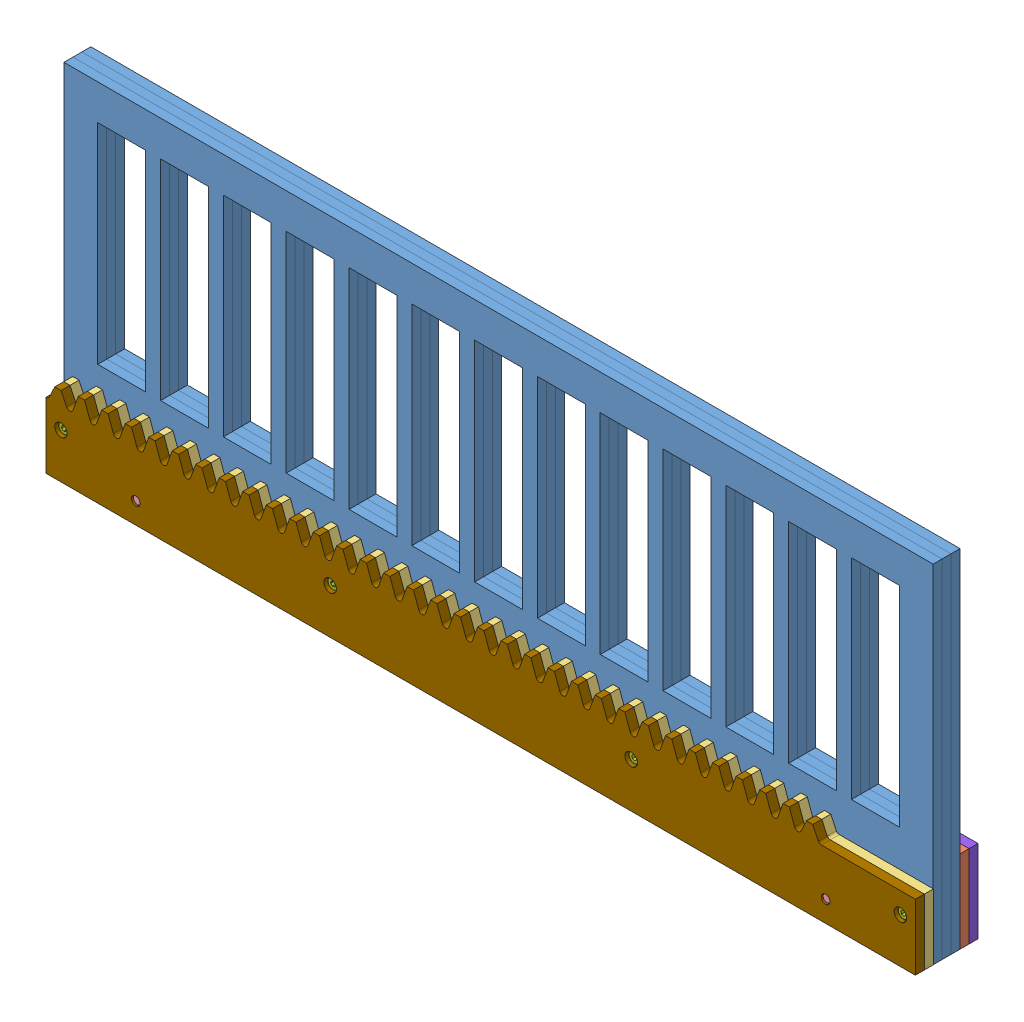
SolidWorks assembly grille-complet, configuration Défaut. Lengths in mm.
Overall size (290.66 121.96 23).
19 component instances, 9 part files, 44 mates.
Components (placement in the parent):
- grille-1: grille [Défaut] at (-123.12 -59.7841 0) size (290.6 116 3)
- grille-bas-1-1: grille-bas-1 [Défaut] at (-123.1215 -59.7841 -3) size (290.6 27.62 3)
- grille-cremaillere-1-1: grille-cremaillere-1 [Défaut] at (151.8274 -59.7841 12) x (-1 0 0) z (0 0 -1) size (290.66 27.62 3)
- grille-axe-d3x20-1: grille-axe-d3x20 [Défaut] at (-97.0485 -52.7841 -5.5) x (0.990021 0.140917 0) z (0.140917 -0.990021 0) size (3 20 3)
- grille-poulie-d20-1: grille-poulie-d20 [Défaut] at (-97.0485 -52.7841 3.2376) x (0.249924 -0.968265 0) z (-0.968265 -0.249924 0) size (20.21 12 20.21)
- grille-poulie-d20-2: grille-poulie-d20 [Défaut] at (133.5488 -52.7841 3.6069) x (0.939295 0.34311 0) z (0.34311 -0.939295 0) size (20.21 12 20.21)
- grille-axe-d3x20-2: grille-axe-d3x20 [Défaut] at (133.5488 -52.7841 -5.5) x (0.725366 0.688363 0) z (0.688363 -0.725366 0) size (3 20 3)
- ecrou-h-1: ecrou-h [6007 HU M2] at (-122.0485 -44.7841 -3) x (1 0 0) z (0 -1 0) size (4 1.6 4.62)
- vis-chc-1: vis-chc [Vis CHC M2x20] at (-122.0485 -44.7841 12) x (-0.903483 -0.428623 0) z (-0.428623 0.903483 0) size (3.8 22 3.8)
- vis-chc-2: vis-chc [Vis CHC M2x20] at (-32.0485 -44.7841 12) x (0.724363 -0.689419 0) z (-0.689419 -0.724363 0) size (3.8 22 3.8)
- vis-chc-3: vis-chc [Vis CHC M2x20] at (68.6083 -44.7841 12) x (0.282213 -0.959352 0) z (-0.959352 -0.282213 0) size (3.8 22 3.8)
- vis-chc-4: vis-chc [Vis CHC M2x20] at (158.6083 -44.7841 12) x (-0.282213 0.959352 0) z (0.959352 0.282213 0) size (3.8 22 3.8)
- grille-2: grille [Défaut] at (-123.12 -59.7841 3) size (290.6 116 3)
- grille-3: grille [Défaut] at (-123.12 -59.7841 6) size (290.6 116 3)
- grille-bas-2-1: grille-bas-2 [Défaut] at (-123.1215 -59.7841 -6) size (290.6 27.62 3)
- grille-cremaillere-2-1: grille-cremaillere-2 [Défaut] at (151.8274 -59.7841 15) x (-1 0 0) z (0 0 -1) size (290.66 27.62 3)
- ecrou-h-2: ecrou-h [6007 HU M2] at (-32.0485 -44.7841 -3) x (1 0 0) z (0 -1 0) size (4 1.6 4.62)
- ecrou-h-3: ecrou-h [6007 HU M2] at (68.6083 -44.7841 -3) x (1 0 0) z (0 -1 0) size (4 1.6 4.62)
- ecrou-h-4: ecrou-h [6007 HU M2] at (158.6083 -44.7841 -3) x (1 0 0) z (0 -1 0) size (4 1.6 4.62)
Mates (geometry in assembly coordinates):
- Coïncidente7: coincident anti-aligned: line of grille-axe-d3x20-1 through (-97.0485 -52.7841 14.3) axis (0 0 -1); line of grille-poulie-d20-1 through (-97.0485 -52.7841 3.2376) axis (0 0 1)
- Coïncidente12: coincident anti-aligned: line of Poulie D20-2 through (133.5488 -52.7841 3.6069) axis (0 0 1); line of grille-axe-d3x20-2 through (133.5488 -52.7841 14.3) axis (0 0 -1)
- Coïncidente22: coincident anti-aligned: plane of grille-1 through (-107.05 -50.784 3) normal (0 0 1); plane of grille-2 through (-107.05 -50.784 3) normal (0 0 -1)
- Coïncidente23: coincident aligned: plane of grille-1 through (-127.0485 56.2159 3) normal (0 1 0); plane of grille-2 through (-127.0485 56.2159 6) normal (0 1 0)
- Coïncidente24: coincident: line of grille-1 through (116 163.5503 -59.7841) axis (0 0 1); plane of grille-2 through (163.5503 56.2159 6) normal (1 0 0)
- Coïncidente26: coincident anti-aligned: plane of grille-2 through (-107.05 -50.784 6) normal (0 0 1); plane of grille-3 through (-107.05 -50.784 6) normal (0 0 -1)
- Coïncidente27: coincident aligned: plane of grille-2 through (-127.0485 56.2159 6) normal (0 1 0); plane of grille-3 through (-127.0485 56.2159 9) normal (0 1 0)
- Coïncidente28: coincident aligned: plane of grille-2 through (163.5503 56.2159 6) normal (1 0 0); plane of grille-3 through (163.5503 56.2159 9) normal (1 0 0)
- Coïncidente29: coincident aligned: plane of grille-1 through (-127.0485 56.2159 3) normal (-1 0 0); plane of grille-bas-1-1 through (-127.0485 -32.1591 0) normal (-1 0 0)
- Coïncidente30: coincident anti-aligned: plane of grille-1 through (-107.05 -50.784 0) normal (0 0 -1); plane of grille-bas-1-1 through (-127.0485 -59.7841 0) normal (0 0 1)
- Coïncidente32: coincident anti-aligned: plane of grille-cremaillere-1-1 through (124.3384 -36.6044 9) normal (0 0 -1); plane of grille-3 through (-107.05 -50.784 9) normal (0 0 1)
- Coïncidente33: coincident aligned: plane of grille-cremaillere-1-1 through (-127.0485 -37.7826 9) normal (-1 0 0); plane of grille-3 through (-127.0485 56.2159 9) normal (-1 0 0)
- Coïncidente35: coincident aligned: plane of grille-cremaillere-1-1 through (-127.0485 -59.7841 9) normal (0 -1 0); plane of grille-3 through (163.5503 -59.7841 9) normal (0 -1 0)
- Coïncidente36: coincident aligned: plane of grille-bas-1-1 through (-127.0485 -59.7841 0) normal (0 -1 0); plane of grille-cremaillere-1-1 through (-127.0485 -59.7841 9) normal (0 -1 0)
- Coïncidente37: coincident aligned: plane of grille-bas-1-1 through (-127.0485 -32.1591 0) normal (-1 0 0); plane of grille-bas-2-1 through (-127.0485 -32.1591 -3) normal (-1 0 0)
- Coïncidente38: coincident anti-aligned: plane of grille-bas-1-1 through (-127.0485 -59.7841 -3) normal (0 0 -1); plane of grille-bas-2-1 through (-127.0485 -59.7841 -3) normal (0 0 1)
- Coïncidente39: coincident aligned: plane of grille-bas-1-1 through (-127.0485 -32.1591 0) normal (0 1 0); plane of grille-bas-2-1 through (-127.0485 -32.1591 -3) normal (0 1 0)
- Coïncidente40: coincident aligned: plane of grille-cremaillere-1-1 through (163.6083 -37.7841 9) normal (1 0 0); plane of grille-cremaillere-2-1 through (163.6083 -37.7841 12) normal (1 0 0)
- Coïncidente41: coincident aligned: plane of grille-cremaillere-1-1 through (-127.0485 -59.7841 9) normal (0 -1 0); plane of grille-cremaillere-2-1 through (-127.0485 -59.7841 12) normal (0 -1 0)
- Coïncidente42: coincident anti-aligned: plane of grille-cremaillere-1-1 through (124.3384 -36.6044 12) normal (0 0 1); plane of grille-cremaillere-2-1 through (124.3384 -36.6044 12) normal (0 0 -1)
- Coaxiale2: concentric anti-aligned: cylinder of grille-axe-d3x20-2 through (133.5488 -52.7841 14.5) axis (0 0 -1) radius 1.5; cylinder of grille-bas-2-1 through (133.5488 -52.7841 -6) axis (0 0 1) radius 1.45
- Distance1: distance = 0.5 mm aligned: plane of grille-axe-d3x20-2 through (133.5488 -52.7841 -5.5) normal (0 0 -1); plane of grille-bas-2-1 through (-127.0485 -59.7841 -6) normal (0 0 -1)
- Coaxiale3: concentric aligned: cylinder of grille-axe-d3x20-1 through (-97.0485 -52.7841 14.5) axis (0 0 -1) radius 1.5; cylinder of grille-cremaillere-2-1 through (-97.0485 -52.7841 15) axis (0 0 -1) radius 1.45
- Distance2: distance = 0.5 mm aligned: plane of grille-axe-d3x20-1 through (-97.0485 -52.7841 -5.5) normal (0 0 -1); plane of grille-bas-2-1 through (-127.0485 -59.7841 -6) normal (0 0 -1)
- Coaxiale4: concentric aligned: cylinder of grille-cremaillere-2-1 through (-122.0485 -44.7841 12) axis (0 0 1) radius 2.1; cylinder of vis-chc-1 through (-122.0485 -44.7841 -8) axis (0 0 1) radius 1
- Coïncidente45: coincident anti-aligned: plane of grille-cremaillere-1-1 through (124.3384 -36.6044 12) normal (0 0 1); plane of vis-chc-1 through (-122.0485 -44.7841 12) normal (0 0 -1)
- Coaxiale7: concentric aligned: cylinder of grille-cremaillere-1-1 through (-32.0485 -44.7841 9) axis (0 0 1) radius 1.1; cylinder of vis-chc-2 through (-32.0485 -44.7841 -8) axis (0 0 1) radius 1
- Coaxiale8: concentric aligned: cylinder of grille-cremaillere-1-1 through (68.6083 -44.7841 9) axis (0 0 1) radius 1.1; cylinder of vis-chc-3 through (68.6083 -44.7841 -8) axis (0 0 1) radius 1
- Coaxiale9: concentric aligned: cylinder of grille-cremaillere-1-1 through (158.6083 -44.7841 9) axis (0 0 1) radius 1.1; cylinder of vis-chc-4 through (158.6083 -44.7841 -8) axis (0 0 1) radius 1
- Coïncidente46: coincident anti-aligned: plane of grille-cremaillere-1-1 through (124.3384 -36.6044 12) normal (0 0 1); plane of vis-chc-2 through (-32.0485 -44.7841 12) normal (0 0 -1)
- Coïncidente47: coincident aligned: circle of grille-cremaillere-2-1; plane of vis-chc-3 through (68.6083 -44.7841 12) normal (0 0 -1)
- Coïncidente48: coincident anti-aligned: plane of grille-cremaillere-1-1 through (124.3384 -36.6044 12) normal (0 0 1); plane of vis-chc-4 through (158.6083 -44.7841 12) normal (0 0 -1)
- Coaxiale10: concentric aligned: cylinder of ecrou-h-1 through (-122.0485 -44.7841 -4.6) axis (0 0 1) radius 0.7835; cylinder of vis-chc-1 through (-122.0485 -44.7841 -8) axis (0 0 1) radius 1
- Parallèle1: parallel anti-aligned: plane of grille-bas-2-1 through (-124.2136 -46.0341 -3) normal (1 0 0); plane of ecrou-h-1 through (-124.0485 -43.6294 -4.6) normal (-1 0 0)
- Coïncidente50: coincident anti-aligned: plane of grille-bas-1-1 through (-127.0485 -59.7841 -3) normal (0 0 -1); plane of ecrou-h-1 through (-120.0485 -43.6294 -3) normal (0 0 1)
- Coaxiale11: concentric aligned: cylinder of vis-chc-2 through (-32.0485 -44.7841 -8) axis (0 0 1) radius 1; cylinder of ecrou-h-2 through (-32.0485 -44.7841 -4.6) axis (0 0 1) radius 0.7835
- Coaxiale12: concentric aligned: cylinder of vis-chc-3 through (68.6083 -44.7841 -8) axis (0 0 1) radius 1; cylinder of ecrou-h-3 through (68.6083 -44.7841 -4.6) axis (0 0 1) radius 0.7835
- Coaxiale13: concentric aligned: cylinder of vis-chc-4 through (158.6083 -44.7841 -8) axis (0 0 1) radius 1; cylinder of ecrou-h-4 through (158.6083 -44.7841 -4.6) axis (0 0 1) radius 0.7835
- Parallèle2: parallel anti-aligned: plane of grille-bas-2-1 through (-34.2136 -43.5341 -3) normal (0.5 -0.866025 0); plane of ecrou-h-2 through (-32.0485 -42.4747 -4.6) normal (-0.5 0.866025 0)
- Parallèle3: parallel anti-aligned: plane of grille-bas-2-1 through (66.3838 -43.5341 -3) normal (0.5 -0.866025 0); plane of ecrou-h-3 through (68.6083 -42.4747 -4.6) normal (-0.5 0.866025 0)
- Parallèle4: parallel anti-aligned: plane of grille-bas-2-1 through (156.3838 -43.5341 -3) normal (0.5 -0.866025 0); plane of ecrou-h-4 through (158.6083 -42.4747 -4.6) normal (-0.5 0.866025 0)
- Coïncidente55: coincident anti-aligned: plane of grille-bas-1-1 through (-127.0485 -59.7841 -3) normal (0 0 -1); plane of ecrou-h-2 through (-30.0485 -43.6294 -3) normal (0 0 1)
- Coïncidente56: coincident anti-aligned: plane of grille-bas-1-1 through (-127.0485 -59.7841 -3) normal (0 0 -1); plane of ecrou-h-3 through (70.6083 -43.6294 -3) normal (0 0 1)
- Coïncidente57: coincident anti-aligned: plane of grille-bas-1-1 through (-127.0485 -59.7841 -3) normal (0 0 -1); plane of ecrou-h-4 through (160.6083 -43.6294 -3) normal (0 0 1)
